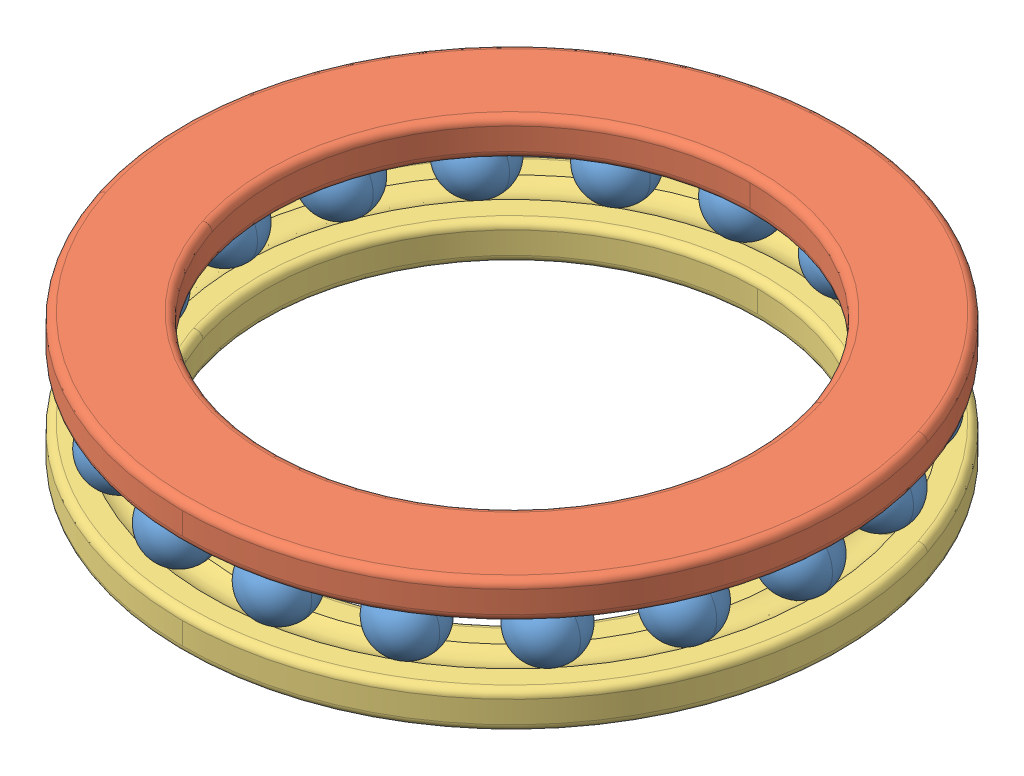
SolidWorks assembly 51113, configuration Default. Lengths in mm.
Overall size (90 18 90).
20 component instances, 3 part files, 0 mates.
Components (placement in the parent):
- 51113_3-1: 51113_3 [Default] at (-36.8829 9 -13.4243) x (0 -1 0) z (0 0 1) size (9 9 9)
- 51113_3-2: 51113_3 [Default] at (-30.0672 9 -25.2294) x (0 -1 0) z (0 0 1) size (9 9 9)
- 51113_3-3: 51113_3 [Default] at (-19.625 9 -33.9915) x (0 -1 0) z (0 0 1) size (9 9 9)
- 51113_3-4: 51113_3 [Default] at (-6.8157 9 -38.6537) x (0 -1 0) z (0 0 1) size (9 9 9)
- 51113_3-5: 51113_3 [Default] at (6.8157 9 -38.6537) x (0 -1 0) z (0 0 1) size (9 9 9)
- 51113_3-6: 51113_3 [Default] at (19.625 9 -33.9915) x (0 -1 0) z (0 0 1) size (9 9 9)
- 51113_3-7: 51113_3 [Default] at (30.0672 9 -25.2294) x (0 -1 0) z (0 0 1) size (9 9 9)
- 51113_3-8: 51113_3 [Default] at (36.8829 9 -13.4243) x (0 -1 0) z (0 0 1) size (9 9 9)
- 51113_3-9: 51113_3 [Default] at (39.25 9 0) x (0 -1 0) z (0 0 1) size (9 9 9)
- 51113_3-10: 51113_3 [Default] at (36.8829 9 13.4243) x (0 -1 0) z (0 0 1) size (9 9 9)
- 51113_3-11: 51113_3 [Default] at (30.0672 9 25.2294) x (0 -1 0) z (0 0 1) size (9 9 9)
- 51113_3-12: 51113_3 [Default] at (19.625 9 33.9915) x (0 -1 0) z (0 0 1) size (9 9 9)
- 51113_3-13: 51113_3 [Default] at (6.8157 9 38.6537) x (0 -1 0) z (0 0 1) size (9 9 9)
- 51113_3-14: 51113_3 [Default] at (-6.8157 9 38.6537) x (0 -1 0) z (0 0 1) size (9 9 9)
- 51113_3-15: 51113_3 [Default] at (-19.625 9 33.9915) x (0 -1 0) z (0 0 1) size (9 9 9)
- 51113_3-16: 51113_3 [Default] at (-30.0672 9 25.2294) x (0 -1 0) z (0 0 1) size (9 9 9)
- 51113_3-17: 51113_3 [Default] at (-36.8829 9 13.4243) x (0 -1 0) z (0 0 1) size (9 9 9)
- 51113_3-18: 51113_3 [Default] at (-39.25 9 0) x (0 -1 0) z (0 0 1) size (9 9 9)
- 51113_22-1: 51113_22 [Default] at (0 13 0) x (0 1 0) z (0 0 1) size (5 90 90)
- 51113_24-1: 51113_24 [Default] at origin size (90 5 90)
